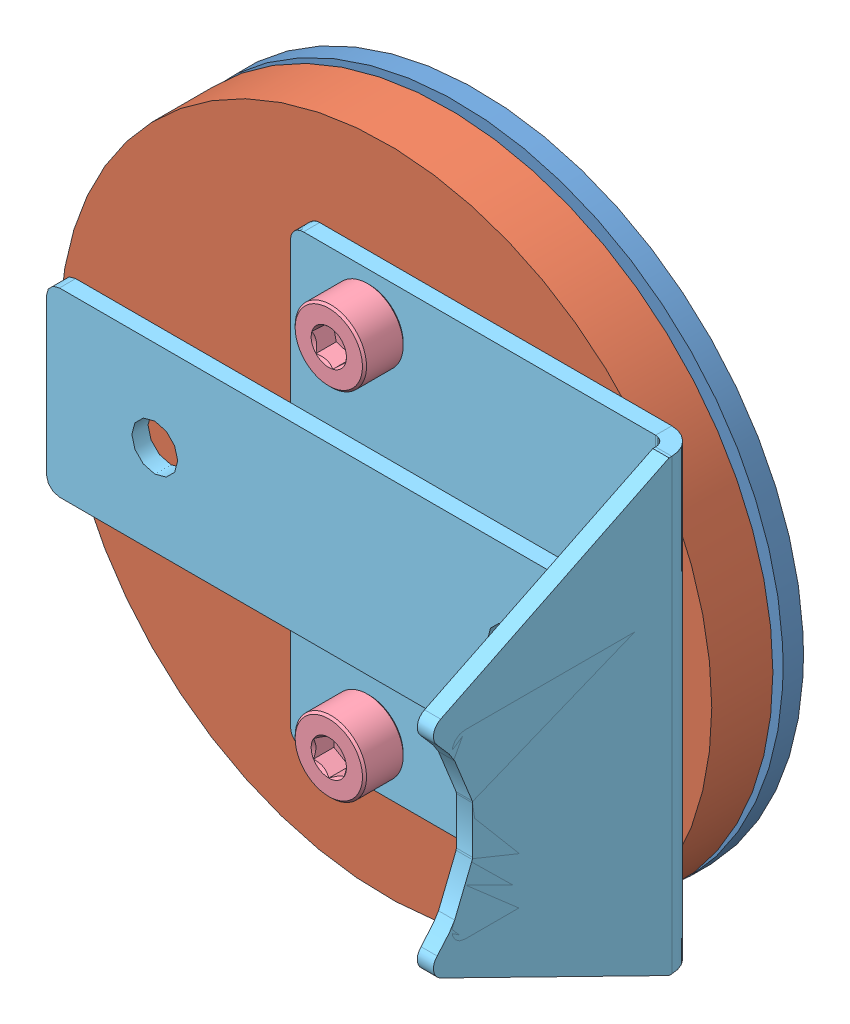
SolidWorks assembly EL-A0105-AA-TSAL Assembly, configuration Default. Lengths in mm.
Overall size (64 64 34.98).
7 component instances, 5 part files, 11 mates.
Components (placement in the parent):
- EL-50071-AA-TSAL Bottom Housing-1: EL-50071-AA-TSAL Bottom Housing [Default] at (31.8158 48.3259 30.7086) size (64 64 7)
- EL-50070-AA-TSAL Top Housing-1: EL-50070-AA-TSAL Top Housing [Default] at (31.8158 48.3259 37.7086) x (-1 0 0) z (0 0 -1) size (64 64 6)
- FS-Heat Set Insert, M4x7-4.7 (94180A351)-1: FS-Heat Set Insert, M4x7-4.7 (94180A351) [94180A351] at (31.8158 65.7757 34.3586) x (0.903343 0.428919 0) z (0 0 1) size (6.35 6.35 4.7)
- BR-Black Oxide C12.9 SHCS, M4x0.7-8 (91290A140)-1: BR-Black Oxide C12.9 SHCS, M4x0.7-8 (91290A140) [91290A140] at (31.8158 30.8761 38.2961) size (7 7 12.17)
- BR-Black Oxide C12.9 SHCS, M4x0.7-8 (91290A140)-2: BR-Black Oxide C12.9 SHCS, M4x0.7-8 (91290A140) [91290A140] at (31.8158 65.7761 38.2961) x (0.974093 0.226149 0) z (0 0 1) size (7 7 12.17)
- FS-Heat Set Insert, M4x7-4.7 (94180A351)-2: FS-Heat Set Insert, M4x7-4.7 (94180A351) [94180A351] at (31.8158 30.8761 34.3586) x (0.999993 0.003625 0) z (0 0 1) size (6.35 6.35 4.7)
- EL-30072-AA-TSAL Mounting Tab-2: EL-30072-AA-TSAL Mounting Tab [Default] at (60.8908 48.3261 73.3161) x (0 -1 0) z (0 0 -1) size (44 58.74 25.98)
Mates (geometry in assembly coordinates):
- Concentric1: concentric anti-aligned: cone of EL-500XX-AA-TSAL Bottom Housing-1 through (31.8158 30.8761 36.7086) axis (0 0 -1); cylinder of EL-50070-AA-TSAL Top Housing-1 through (31.8158 30.8761 38.7086) axis (0 0 1) radius 2.4
- Concentric2: concentric anti-aligned: cone of EL-500XX-AA-TSAL Bottom Housing-1 through (31.8158 65.7757 36.7086) axis (0 0 -1); cylinder of EL-50070-AA-TSAL Top Housing-1 through (31.8158 65.7757 38.7086) axis (0 0 1) radius 2.4
- Concentric3: concentric anti-aligned: cylinder of EL-500XX-AA-TSAL Bottom Housing-1 through (31.8158 48.3259 36.7086) axis (0 0 -1) radius 30; cylinder of EL-50070-AA-TSAL Top Housing-1 through (31.8158 48.3259 32.7086) axis (0 0 1) radius 30.05
- Coincident1: coincident aligned: plane of EL-500XX-AA-TSAL Bottom Housing-1 through (31.8158 48.3259 36.7086) normal (0 0 1); circle of EL-500XX-AA-TSAL Top Housing-1
- Concentric7: concentric anti-aligned: cone of EL-50071-AA-TSAL Bottom Housing-1 through (31.8158 65.7757 36.7086) axis (0 0 -1); cylinder of FS-Heat Set Insert, M4x7-4.7 (94180A351)-1 through (31.8158 65.7757 36.7086) axis (0 0 1) radius 3.175
- Coincident3: coincident aligned: plane of EL-50071-AA-TSAL Bottom Housing-1 through (31.8158 48.3259 36.7086) normal (0 0 1); circle of FS-Heat Set Insert, M4x7-4.7 (94180A351)-1
- Concentric8: concentric anti-aligned: cone of EL-50071-AA-TSAL Bottom Housing-1 through (31.8158 30.8761 36.7086) axis (0 0 -1); cylinder of FS-Heat Set Insert, M4x7-4.7 (94180A351)-2 through (31.8158 30.8761 36.7086) axis (0 0 1) radius 3.175
- Coincident4: coincident aligned: plane of EL-50071-AA-TSAL Bottom Housing-1 through (31.8158 48.3259 36.7086) normal (0 0 1); circle of FS-Heat Set Insert, M4x7-4.7 (94180A351)-2
- Concentric9: concentric aligned: cylinder of EL-50070-AA-TSAL Top Housing-1 through (31.8158 65.7757 38.7086) axis (0 0 1) radius 2.4; cylinder of EL-30072-BA-TSAL Mounting Tab-1 through (31.8158 65.7761 40.2961) axis (0 0 1) radius 2.25
- Concentric10: concentric aligned: cylinder of EL-50070-AA-TSAL Top Housing-1 through (31.8158 30.8761 38.7086) axis (0 0 1) radius 2.4; cylinder of EL-30072-BA-TSAL Mounting Tab-1 through (31.8158 30.8761 40.2961) axis (0 0 1) radius 2.25
- Coincident5: coincident anti-aligned: plane of EL-50070-AA-TSAL Top Housing-1 through (31.8158 48.3259 38.7086) normal (0 0 1); plane of EL-30072-BA-TSAL Mounting Tab-1 through (60.8908 48.3261 38.7086) normal (0 0 -1)
